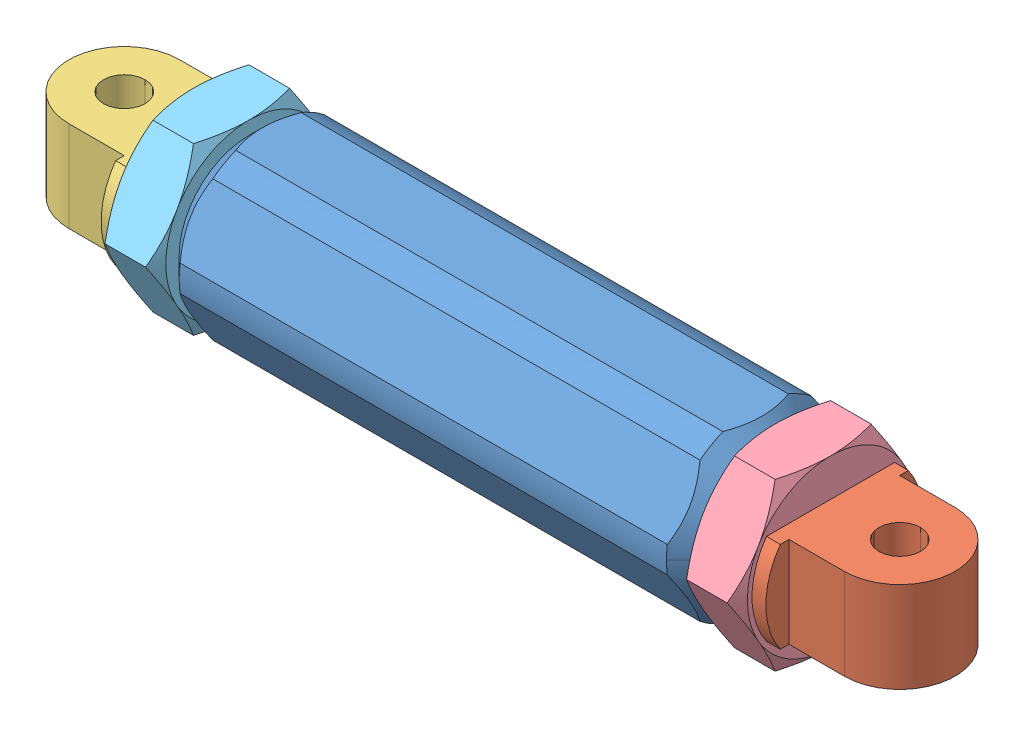
SolidWorks assembly WCP-0247 (2).step, configuration Default. Lengths in mm.
Overall size (50.8 11.02 11.02).
5 component instances, 5 part files, 0 mates.
Components (placement in the parent):
- WCP-0247-001 Rev2.step-1: WCP-0247-001 Rev2.step [Default] at origin size (30.16 9.53 10.24)
- WCP-0247-002 Rev2.step-1: WCP-0247-002 Rev2.step [Default] at (22.225 0 0) x (0 0 1) z (0 1 0) size (9 23.02 5.21)
- WCP-0247-003 Rev2.step-1: WCP-0247-003 Rev2.step [Default] at (-22.225 0 0) x (0 0 -1) z (0 1 0) size (9 23.02 5.21)
- WCP-0247-004 Rev1.step-1: WCP-0247-004 Rev1.step [Default] at (16.6687 0 0) x (0 -1 0) z (0 0 1) size (11.02 3.19 11.02)
- WCP-0247-005 Rev1.step-1: WCP-0247-005 Rev1.step [Default] at (-16.6687 0 0) x (0 -1 0) z (0 0 1) size (11.02 3.19 11.02)
